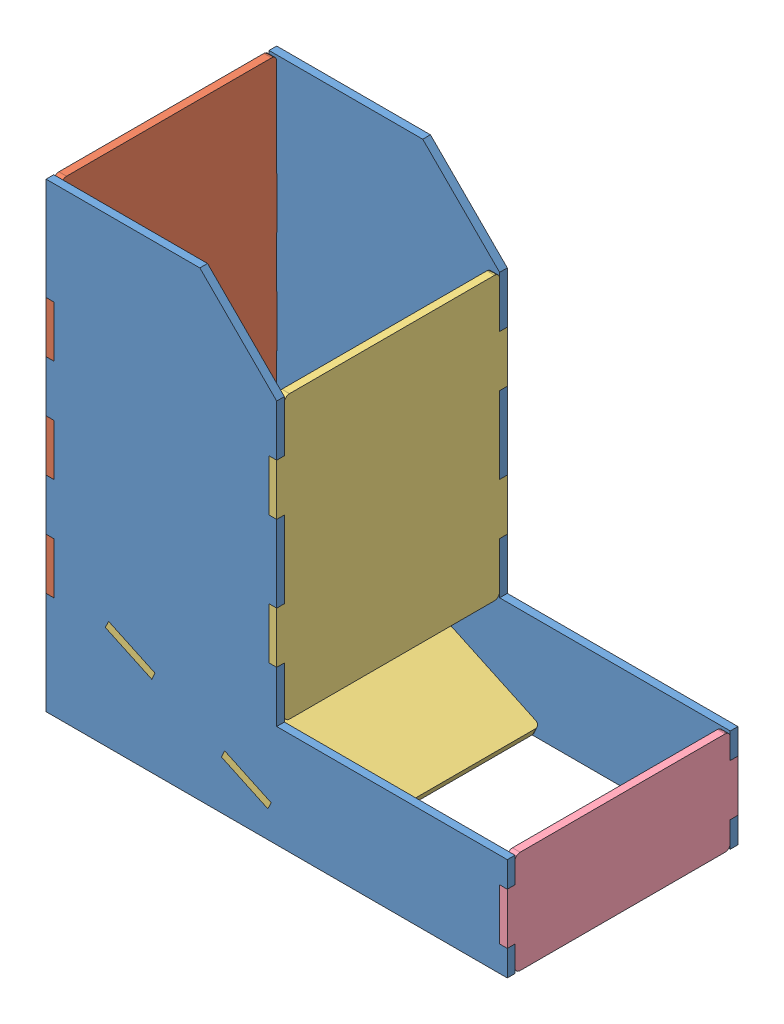
SolidWorks assembly tower, configuration Default. Lengths in mm.
Overall size (180 180 90).
6 component instances, 4 part files, 7 mates.
Components (placement in the parent):
- side panel-1: side panel [Default] at origin size (180 180 3)
- side panel-2: side panel [Default] at (0 0 -87) size (180 180 3)
- back panel-1: back panel [Default] at origin size (3 180 90)
- center panel-1: center panel [Default] at origin size (3 110 90)
- front panel-1: front panel [Default] at origin size (3 40 90)
- center panel-2: center panel [Default] at (-9.5022 -46.5153 0) x (0.422618 0.906308 0) z (0 0 1) size (3 110 90)
Mates (geometry in assembly coordinates):
- Coincident1: coincident aligned: plane of side panel-1 through (86.0851 0 1.5) normal (1 0 0); plane of side panel-2 through (86.0851 0 -85.5) normal (1 0 0)
- Coincident2: coincident aligned: plane of side panel-1 through (0 -25.6023 1.5) normal (0 1 0); plane of side panel-2 through (0 -25.6023 -85.5) normal (0 1 0)
- Distance1: distance anti-aligned: plane of side panel-1 through (0 0 1.5) normal (0 0 1); plane of side panel-2 through (0 0 -88.5) normal (0 0 -1)
- Angle1: planar angle = 0.436332 rad anti-aligned: plane of back panel-1 through (-90.9149 -65.6023 -268.525) normal (0 -1 0); plane of center panel-2 through (-87.647 -14.3954 -198.5409) normal (0.422618 0.906308 0)
- Coincident3: coincident aligned: plane of side panel-1 through (0 0 1.5) normal (0 0 1); plane of center panel-2 through (-9.5022 -46.5153 1.5) normal (0 0 1)
- Distance2: distance = 2 mm: line of center panel-2 through (-88.9149 -17.1143 -83.5) axis (0 0 1); plane of back panel-1 through (-90.9149 114.3977 -268.525) normal (1 0 0)
- Distance3: distance = 2 mm: plane of side panel-1 through (0 -65.6023 1.5) normal (0 -1 0); line of center panel-2 through (10.779 -63.6023 -83.5) axis (0 0 1)
